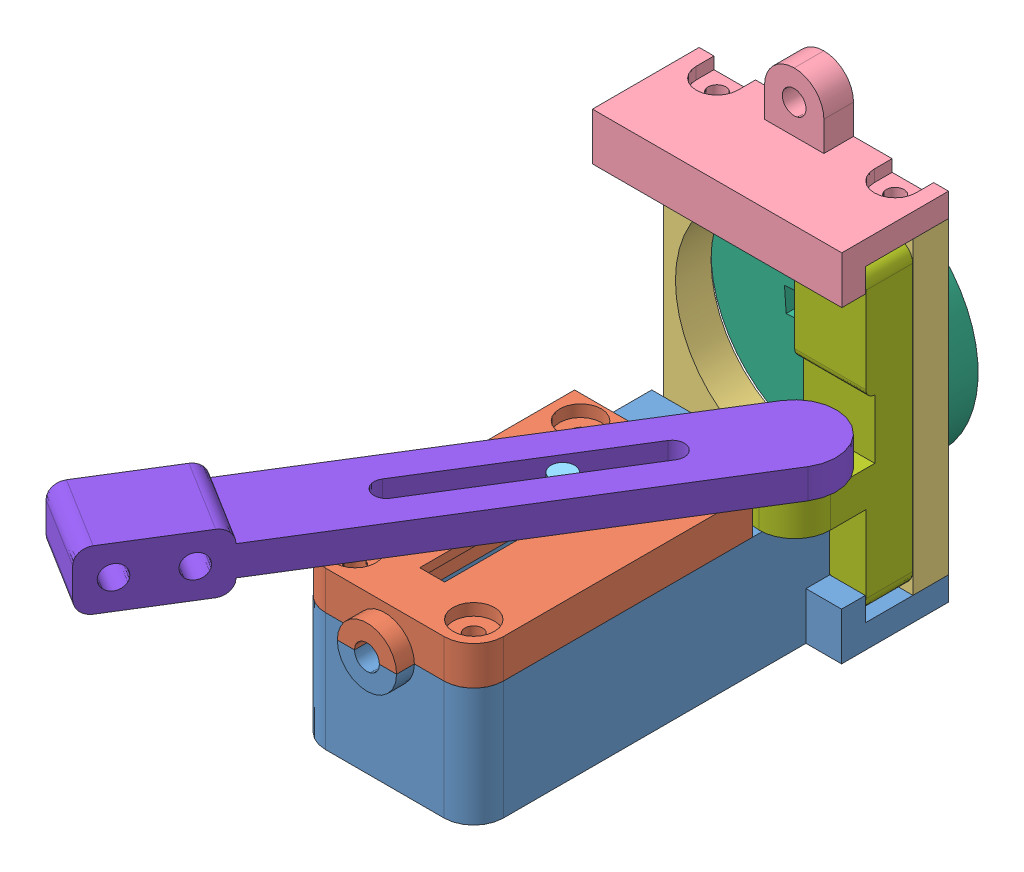
SolidWorks assembly Assem2, configuration Default. Lengths in mm.
Overall size (63.1 80 106.08).
8 component instances, 8 part files, 20 mates.
Components (placement in the parent):
- bottom frame-1: bottom frame [Default] at (34.7629 29.4815 67.468) size (42 30 83.2)
- frame cover-1: frame cover [Default] at (34.7629 49.4815 79.468) size (30 6.5 50)
- middle frame-1: middle frame [Default] at (34.7629 59.4815 31.9555) x (1 0 -0.000833) z (0 -1 0) size (42 6 52)
- top frame-1: top frame [Default] at (34.7679 89.4815 37.9555) x (1 0 -0.000833) z (-0.000833 0 -1) size (42 18 18)
- sliding block-1: sliding block [Default] at (34.7629 49.4815 72.968) x (0 0 1) z (-1 0 0) size (8 15 9.5)
- rotating wheel-1: rotating wheel [Default] at (34.7554 59.4815 22.9555) x (-0.997501 -0.070652 0.000831) z (0.000833 0 1) size (40 40 16)
- sliding stick-2: sliding stick [Default] at (49.7813 59.4815 38.9429) x (0 1 0) z (1 0 -0.000833) size (50 19.9 12)
- bar-2: bar [Default] at (49.7895 61.0815 48.8929) x (0.52799 0 -0.84925) z (-0.84925 0 -0.52799) size (97 10 14)
Mates (geometry in assembly coordinates):
- Concentric1: concentric anti-aligned: circle of bottom frame-1; circle of frame cover-1
- Concentric2: concentric anti-aligned: circle of bottom frame-1; circle of frame cover-1
- Coincident1: coincident anti-aligned: plane of bottom frame-1 through (34.7629 49.4815 67.468) normal (0 1 0); plane of frame cover-1 through (34.7629 49.4815 79.468) normal (0 -1 0)
- Concentric3: concentric aligned: circle of bottom frame-1; circle of middle frame-1
- Concentric4: concentric anti-aligned: circle of bottom frame-1; circle of middle frame-1
- Coincident4: coincident anti-aligned: plane of bottom frame-1 through (34.7629 33.4815 67.468) normal (0 1 0); plane of middle frame-1 through (55.7654 33.4815 34.938) normal (0 -1 0)
- Concentric5: concentric anti-aligned: circle of middle frame-1; circle of top frame-1
- Concentric6: concentric anti-aligned: circle of middle frame-1; circle of top frame-1
- Coincident5: coincident anti-aligned: plane of middle frame-1 through (55.7654 85.4815 34.938) normal (0 1 0); plane of top frame-1 through (34.7679 85.4815 37.9555) normal (0 -1 0)
- Concentric8: concentric anti-aligned: circle of bottom frame-1; circle of sliding block-1
- Distance2: distance = 18 mm anti-aligned: plane of sliding block-1 through (30.0129 53.9815 76.968) normal (0 0 1); plane of bottom frame-1 through (29.7629 44.4815 94.968) normal (0 0 -1)
- Parallel1: parallel aligned: plane of bottom frame-1 through (19.7629 29.4815 105.968) normal (-1 0 0); plane of sliding block-1 through (30.0129 53.9815 76.968) normal (-1 0 0)
- Distance3: distance = 1 mm anti-aligned: plane of rotating wheel-1 through (34.7596 59.4815 27.9555) normal (0.000833 0 1); plane of middle frame-1 through (34.7604 59.4815 28.9555) normal (-0.000833 0 -1)
- Concentric9: concentric aligned: circle of middle frame-1; circle of rotating wheel-1
- Distance4: distance = 1 mm anti-aligned: plane of sliding stick-2 through (55.7845 34.4815 42.8879) normal (0 -1 0); plane of bottom frame-1 through (34.7629 33.4815 67.468) normal (0 1 0)
- Tangent8: tangent anti-aligned: cylinder of rotating wheel-1 through (49.7313 60.5413 38.943) axis (-0.000833 0 -1) radius 3; plane of sliding stick-2 through (46.7313 78.4815 38.9955) normal (1 0 -0.000833)
- Distance6: distance = 0.05 mm anti-aligned: plane of sliding stick-2 through (49.7845 59.4815 42.8929) normal (0.000833 0 1); plane of top frame-1 through (13.7721 85.4815 42.973) normal (-0.000833 0 -1)
- Concentric10: concentric anti-aligned: circle of sliding stick-2; circle of bar-2
- Distance7: distance = 0.1 mm anti-aligned: plane of bar-2 through (49.7895 56.0815 48.8929) normal (0 -1 0); plane of sliding stick-2 through (43.7945 55.9815 54.8979) normal (0 1 0)
- Tangent9: tangent anti-aligned: cylinder of sliding block-1 through (34.7629 59.9815 72.968) axis (0 -1 0) radius 2; plane of bar-2 through (21.6491 61.0815 90.2731) normal (0.84925 0 0.52799)
